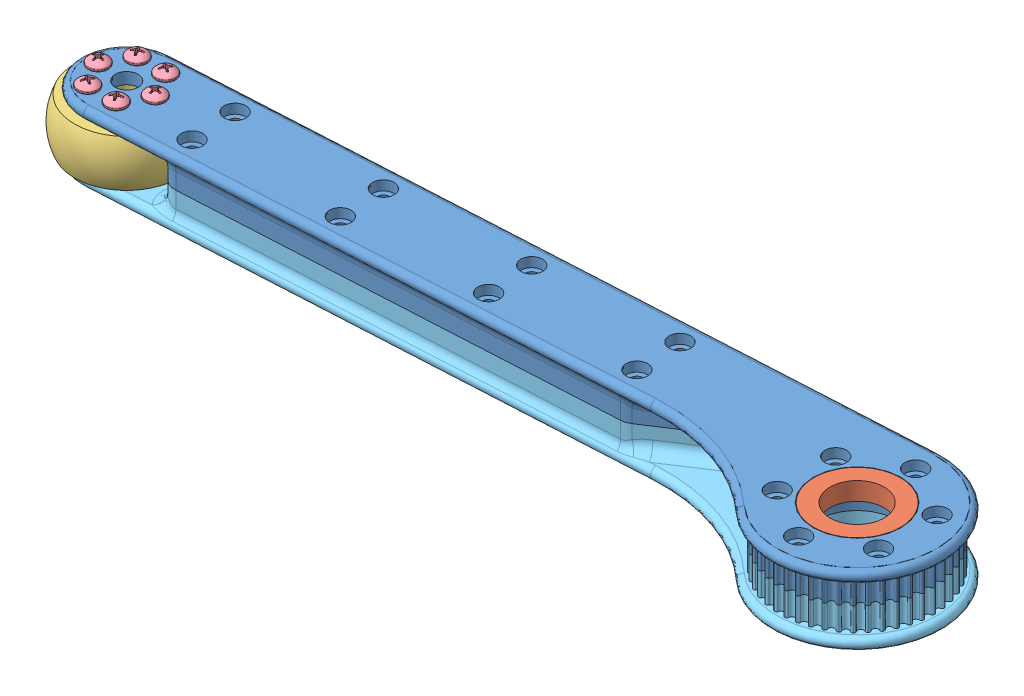
SolidWorks assembly Lower_Extremedy, configuration Default. Lengths in mm.
Overall size (242.89 23.99 47.62).
20 component instances, 7 part files, 19 mates.
Components (placement in the parent):
- Assem1^Lower_Extremedy-1: Assem1^Lower_Extremedy [Default] at origin size (239.71 9.67 47.62) (virtual)
  - Part2^Assem1_Lower_Extremedy-1: Part2^Assem1_Lower_Extremedy [Default] at origin size (239.71 9.67 47.62) (virtual)
  - LowerExtremedyDriven 3htd-1: LowerExtremedyDriven 3htd [Default] at origin size (43.16 13 43.07) (hidden)
  - Side_Plate_Lower-1: Side_Plate_Lower [Default] at (0 8.0875 0) size (239.71 15.88 47.62) (hidden)
- Bearing 15_24_5mm-1: Bearing 15_24_5mm [Default] at (0 7.175 0) size (24 5 24)
- Bearing 15_24_5mm-2: Bearing 15_24_5mm [Default] at (0 -7.175 0) x (1 0 0) z (0 0 -1) size (24 5 24)
- foot-1: foot [Default] at (-203.2 0 0) size (31.75 13 31.75)
- .375 plastight 92295A101_PHILLIPS THREAD-FORMING SCREW FOR PLASTIC-49: .375 plastight 92295A101_PHILLIPS THREAD-FORMING SCREW FOR PLASTIC [92295A101] at (-211.1375 -4.9125 0) x (1 0 0) z (0 -1 0) size (5.56 5.56 13.46)
- .375 plastight 92295A101_PHILLIPS THREAD-FORMING SCREW FOR PLASTIC-50: .375 plastight 92295A101_PHILLIPS THREAD-FORMING SCREW FOR PLASTIC [92295A101] at (-207.1688 -4.9125 6.8741) x (0.5 0 -0.866025) z (0 -1 0) size (5.56 5.56 13.46)
- .375 plastight 92295A101_PHILLIPS THREAD-FORMING SCREW FOR PLASTIC-51: .375 plastight 92295A101_PHILLIPS THREAD-FORMING SCREW FOR PLASTIC [92295A101] at (-199.2312 -4.9125 6.8741) x (-0.5 0 -0.866025) z (0 -1 0) size (5.56 5.56 13.46)
- .375 plastight 92295A101_PHILLIPS THREAD-FORMING SCREW FOR PLASTIC-52: .375 plastight 92295A101_PHILLIPS THREAD-FORMING SCREW FOR PLASTIC [92295A101] at (-195.2625 -4.9125 0) x (-1 0 0) z (0 -1 0) size (5.56 5.56 13.46)
- .375 plastight 92295A101_PHILLIPS THREAD-FORMING SCREW FOR PLASTIC-53: .375 plastight 92295A101_PHILLIPS THREAD-FORMING SCREW FOR PLASTIC [92295A101] at (-199.2312 -4.9125 -6.8741) x (-0.5 0 0.866025) z (0 -1 0) size (5.56 5.56 13.46)
- .375 plastight 92295A101_PHILLIPS THREAD-FORMING SCREW FOR PLASTIC-54: .375 plastight 92295A101_PHILLIPS THREAD-FORMING SCREW FOR PLASTIC [92295A101] at (-207.1688 -4.9125 -6.8741) x (0.5 0 0.866025) z (0 -1 0) size (5.56 5.56 13.46)
- .375 plastight 92295A101_PHILLIPS THREAD-FORMING SCREW FOR PLASTIC-55: .375 plastight 92295A101_PHILLIPS THREAD-FORMING SCREW FOR PLASTIC [92295A101] at (-211.1375 4.9125 0) x (1 0 0) z (0 1 0) size (5.56 5.56 13.46)
- .375 plastight 92295A101_PHILLIPS THREAD-FORMING SCREW FOR PLASTIC-56: .375 plastight 92295A101_PHILLIPS THREAD-FORMING SCREW FOR PLASTIC [92295A101] at (-207.1688 4.9125 6.8741) x (-0.5 0 0.866025) z (0 1 0) size (5.56 5.56 13.46)
- .375 plastight 92295A101_PHILLIPS THREAD-FORMING SCREW FOR PLASTIC-57: .375 plastight 92295A101_PHILLIPS THREAD-FORMING SCREW FOR PLASTIC [92295A101] at (-199.2312 4.9125 6.8741) x (0.5 0 0.866025) z (0 1 0) size (5.56 5.56 13.46)
- .375 plastight 92295A101_PHILLIPS THREAD-FORMING SCREW FOR PLASTIC-58: .375 plastight 92295A101_PHILLIPS THREAD-FORMING SCREW FOR PLASTIC [92295A101] at (-195.2625 4.9125 0) x (-1 0 0) z (0 1 0) size (5.56 5.56 13.46)
- .375 plastight 92295A101_PHILLIPS THREAD-FORMING SCREW FOR PLASTIC-59: .375 plastight 92295A101_PHILLIPS THREAD-FORMING SCREW FOR PLASTIC [92295A101] at (-199.2312 4.9125 -6.8741) x (0.5 0 -0.866025) z (0 1 0) size (5.56 5.56 13.46)
- .375 plastight 92295A101_PHILLIPS THREAD-FORMING SCREW FOR PLASTIC-60: .375 plastight 92295A101_PHILLIPS THREAD-FORMING SCREW FOR PLASTIC [92295A101] at (-207.1688 4.9125 -6.8741) x (-0.5 0 -0.866025) z (0 1 0) size (5.56 5.56 13.46)
- left side mirrot-1: left side mirrot [Default] at origin size (239.71 9.67 47.62)
Mates (geometry in assembly coordinates):
- Concentric1: concentric aligned: cylinder of Bearing 15_24_5mm-1 through (0 9.675 0) axis (0 -1 0) radius 7.5
- Coincident1: coincident aligned: plane of Bearing 15_24_5mm-1 through (0 7.175 0) normal (0 0 1)
- Concentric3: concentric anti-aligned: cylinder of foot-1 through (-203.2 -6.5 0) axis (0 -1 0) radius 3.175
- Coincident8: coincident aligned: plane of foot-1 through (-203.2 0 0) normal (0 1 0)
- Coincident19: coincident aligned: plane of .375 plastight 92295A101_PHILLIPS THREAD-FORMING SCREW FOR PLASTIC-49 through (-211.1375 -4.9125 0) normal (0 0 1)
- Concentric9: concentric anti-aligned: cylinder of foot-1 through (-211.1375 -6.5 0) axis (0 1 0) radius 1.016; line of .375 plastight 92295A101_PHILLIPS THREAD-FORMING SCREW FOR PLASTIC-49 through (-211.1375 2.1359 0) axis (0 -1 0)
- Parallel3: parallel aligned: plane of Assem1^Lower_Extremedy-1/Center Binding PArt-1 through (-107.1562 0 0) normal (0 0 1)
- Coincident20: coincident aligned: plane of Assem1^Lower_Extremedy-1/Center Binding PArt-1 through (-107.1562 0 0) normal (0 1 0)
- Coincident21: coincident aligned: plane of Assem1^Lower_Extremedy-1/Side_Plate_Lower-1 through (0 8.0875 0) normal (0 0 1)
- Coincident22: coincident aligned: plane of Assem1^Lower_Extremedy-1/Side_Plate_Lower-1 through (0 8.0875 0) normal (1 0 0)
- Concentric13: concentric anti-aligned: cylinder of left side mirrot-1 through (0 -6.5 0) axis (0 1 0) radius 11
- Coincident23: coincident aligned: plane of left side mirrot-1 through (0 0 0) normal (0 0 1)
- Coincident24: coincident aligned: plane of left side mirrot-1 through (0 0 0) normal (0 1 0)
- Coincident25: coincident aligned: plane of Assem1^Lower_Extremedy-1/Part2^Assem1_Lower_Extremedy-1 through (-203.2 14.675 0) normal (0 1 0); plane of Bearing 15_24_5mm-1 through (0 14.675 0) normal (0 1 0)
- Concentric14: concentric aligned: cylinder of Assem1^Lower_Extremedy-1/Part2^Assem1_Lower_Extremedy-1 through (0 6.5 0) axis (0 -1 0) radius 11
- Coincident26: coincident aligned: plane of Assem1^Lower_Extremedy-1/Part2^Assem1_Lower_Extremedy-1 through (0 0 0) normal (0 1 0)
- Coincident27: coincident aligned: plane of Assem1^Lower_Extremedy-1/Part2^Assem1_Lower_Extremedy-1 through (-203.2 9.675 0) normal (0 1 0); plane of Bearing 15_24_5mm-1 through (0 9.675 0) normal (0 1 0)
- Coincident28: coincident aligned: plane of .375 plastight 92295A101_PHILLIPS THREAD-FORMING SCREW FOR PLASTIC-49 through (-211.1375 -4.9125 0) normal (0 0 1)
- Coincident29: coincident anti-aligned: plane of .375 plastight 92295A101_PHILLIPS THREAD-FORMING SCREW FOR PLASTIC-49 through (-211.1375 -9.675 0) normal (0 1 0); plane of left side mirrot-1 through (-203.2 -9.675 0) normal (0 -1 0)
